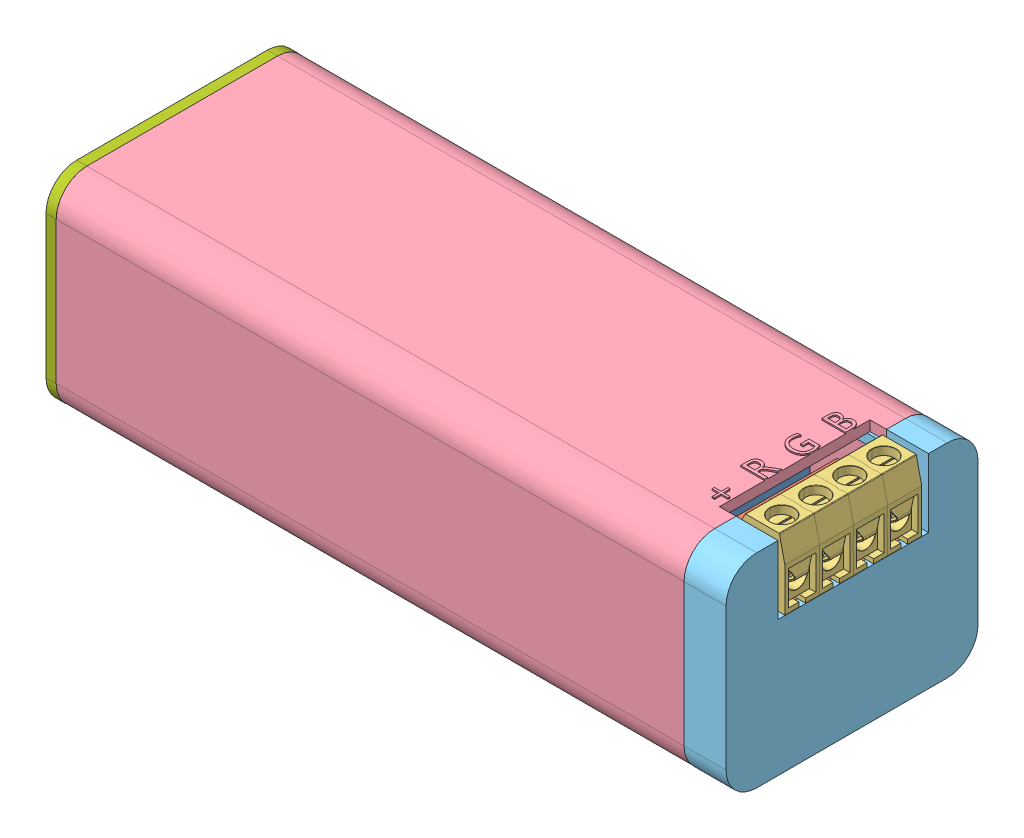
SolidWorks assembly Rgb控制器, configuration 默认. Lengths in mm.
Overall size (102.17 30.1 37).
25 component instances, 7 part files, 16 mates.
Components (placement in the parent):
- RGB控制器主板-1: RGB控制器主板 [默认] at (-52.8533 -25.7477 0) size (58.2 20.9 28)
- RGB.step-1: RGB.step [默认] at (-19.7533 -12.8977 -13.986) x (0 0 1) z (0 1 0) size (27.99 16.17 13.8)
  - Board.step-1: Board.step [默认] at origin size (27.99 15 0.41)
    - Open CASCADE STEP translator 6.8 2.1.1.step-1: Open CASCADE STEP translator 6.8 2.1.1.step [默认] at (0 0 -0.4115) size (27.99 15 0.41)
  - J1.step-1: J1.step [默认] at origin size (20.5 7.6 13.8)
    - KF301-5.0.step-1: KF301-5.0.step [默认] at (65.2753 40.914 0) x (-1 0 0) z (0 0 1) size (5.5 7.6 13.8)
      - Free-Models.step-1: Free-Models.step [默认] at (8.7129 -4.0059 0) size (5.5 7.6 13.8)
        - KF301.step-1: KF301.step [默认] at (35.259 31.75 0.05) size (5.5 7.6 13.8)
          - KF301-0.step-1: KF301-0.step [默认] x (1 0 0) z (0 -1 0) size (5.5 13.8 7.6)
    - KF301-5.0.step-2: KF301-5.0.step [默认] at (60.2753 40.914 0) x (-1 0 0) z (0 0 1) size (5.5 7.6 13.8)
      - Free-Models.step-1: Free-Models.step [默认] at (8.7129 -4.0059 0) size (5.5 7.6 13.8)
        - KF301.step-1: KF301.step [默认] at (35.259 31.75 0.05) size (5.5 7.6 13.8)
          - KF301-0.step-1: KF301-0.step [默认] x (1 0 0) z (0 -1 0) size (5.5 13.8 7.6)
    - KF301-5.0.step-3: KF301-5.0.step [默认] at (55.2753 40.914 0) x (-1 0 0) z (0 0 1) size (5.5 7.6 13.8)
      - Free-Models.step-1: Free-Models.step [默认] at (8.7129 -4.0059 0) size (5.5 7.6 13.8)
        - KF301.step-1: KF301.step [默认] at (35.259 31.75 0.05) size (5.5 7.6 13.8)
          - KF301-0.step-1: KF301-0.step [默认] x (1 0 0) z (0 -1 0) size (5.5 13.8 7.6)
    - KF301-5.0.step-4: KF301-5.0.step [默认] at (50.2753 40.914 0) x (-1 0 0) z (0 0 1) size (5.5 7.6 13.8)
      - Free-Models.step-1: Free-Models.step [默认] at (8.7129 -4.0059 0) size (5.5 7.6 13.8)
        - KF301.step-1: KF301.step [默认] at (35.259 31.75 0.05) size (5.5 7.6 13.8)
          - KF301-0.step-1: KF301-0.step [默认] x (1 0 0) z (0 -1 0) size (5.5 13.8 7.6)
- 外壳主体-1: 外壳主体 [默认] at (-52.8533 -25.7477 14) size (92.2 30.1 37)
- 前部-1: 前部 [默认] at (-19.7533 -13.3092 -13.986) x (0 0 -1) z (0 -1 0) size (37 11.17 29.9)
- 8字AC母坐-1: 8字AC母坐 [默认] at (-103.4533 -17.7977 0) x (0 0 -1) z (0 1 0) size (22 14.7 15)
- 电源端-1: 电源端 [默认] at (-101.9533 -25.7477 14) x (0 0 1) z (-1 0 0) size (37 29.9 6.5)
Mates (geometry in assembly coordinates):
- 重合3: coincident aligned: plane of RGB控制器主板-1 through (-23.7533 -7.3477 14) normal (0 0 1); plane of RGB.step-1/Board.step-1/Open CASCADE STEP translator 6.8 2.1.1.step-1 through (-4.7533 -13.3092 14) normal (0 0 1)
- 距离1: distance = 4 mm: line of RGB.step-1/Board.step-1/Open CASCADE STEP translator 6.8 2.1.1.step-1 through (-19.7533 -12.8977 14) axis (0 0 -1); plane of RGB控制器主板-1 through (-23.7533 -7.3477 14) normal (1 0 0)
- 在位1: in place: plane of RGB控制器主板-1 through (-23.7533 -7.3477 14) normal (0 0 1); plane of ? through (0 0 14) normal (0 0 1); moOrthogonalPlaneRef_w of RGB控制器主板-1 through (-23.7533 -7.3477 14) normal (0 0 1); plane of ? through (0 0 14) normal (0 1 0); plane of RGB控制器主板-1 through (-23.7533 -7.3477 14) normal (0 0 1); plane of ? through (0 0 14) normal (1 0 0); plane of RGB控制器主板-1 through (-23.7533 -7.3477 14) normal (0 0 1); unknown of 外壳主体-1
- 重合4: coincident aligned: plane of ?; plane of ?
- 重合5: coincident aligned: moOrthogonalPlaneRef_w of RGB控制器主板-1 through (-52.8533 -25.7477 14) normal (0 1 0); plane of 外壳主体-1 through (-52.8533 -25.7477 14) normal (0 1 0)
- 重合6: coincident anti-aligned: moOrthogonalPlaneRef_w of RGB控制器主板-1 through (-52.8533 -25.7477 14) normal (-1 0 0); plane of 外壳主体-1 through (-52.8533 -25.7477 14) normal (1 0 0)
- 在位2: in place: plane of ? through (-19.7533 -19.3913 -13.986) normal (0 -1 0); plane of ? through (0 -19.3913 0) normal (0 -1 0); plane of ? through (-19.7533 -19.3913 -13.986) normal (0 -1 0); plane of ? through (0 -19.3913 0) normal (0 0 -1); plane of ? through (-19.7533 -19.3913 -13.986) normal (0 -1 0); plane of ? through (0 -19.3913 0) normal (-1 0 0); plane of RGB.step-1/Board.step-1/Open CASCADE STEP translator 6.8 2.1.1.step-1 through (-19.7533 -13.3092 -13.986) normal (0 -1 0); unknown of 前部-1
- 重合7: coincident aligned: plane of ?; plane of ?
- 重合8: coincident aligned: moOrthogonalPlaneRef_w of RGB.step-1/Board.step-1/Open CASCADE STEP translator 6.8 2.1.1.step-1 through (-19.7533 -13.3092 -13.986) normal (1 0 0); plane of 前部-1 through (-19.7533 -13.3092 -13.986) normal (1 0 0)
- 重合9: coincident anti-aligned: moOrthogonalPlaneRef_w of RGB.step-1/Board.step-1/Open CASCADE STEP translator 6.8 2.1.1.step-1 through (-19.7533 -13.3092 -13.986) normal (0 0 1); plane of 前部-1 through (-19.7533 -13.3092 -13.986) normal (0 0 -1)
- 重合10: coincident aligned: plane of RGB.step-1/J1.step-1/KF301-5.0.step-4/Free-Models.step-1/KF301.step-1/KF301-0.step-1 through (-6.5834 -2.8477 -7.6827) normal (0 1 0); plane of 外壳主体-1 through (-169.5244 -2.8477 -14) normal (0 1 0)
- 在位3: in place: plane of 外壳主体-1 through (-101.9533 -7.3477 14) normal (-1 0 0); plane of ? through (-101.9533 0 0) normal (-1 0 0); plane of 外壳主体-1 through (-101.9533 -7.3477 14) normal (-1 0 0); plane of ? through (-101.9533 0 0) normal (0 1 0); plane of 外壳主体-1 through (-101.9533 -7.3477 14) normal (-1 0 0); plane of ? through (-101.9533 0 0) normal (0 0 1); plane of 外壳主体-1 through (-101.9533 -7.3477 14) normal (-1 0 0); unknown of 电源端-1
- 重合11: coincident aligned: plane of ?; plane of ?
- 重合12: coincident aligned: moOrthogonalPlaneRef_w of 外壳主体-1 through (-101.9533 -25.7477 14) normal (0 1 0); plane of 电源端^Rgb控制器-1 through (-101.9533 -25.7477 14) normal (0 1 0)
- 重合13: coincident anti-aligned: moOrthogonalPlaneRef_w of 外壳主体-1 through (-101.9533 -25.7477 14) normal (0 0 -1); plane of 电源端^Rgb控制器-1 through (-101.9533 -25.7477 14) normal (0 0 1)
- 轮廓中心1: profile center = 2.3 mm aligned: plane of 8字AC母坐-1 through (-105.7533 -17.7977 0) normal (-1 0 0); plane of 电源端^Rgb控制器-1 through (-103.4533 -7.3477 14) normal (-1 0 0)
